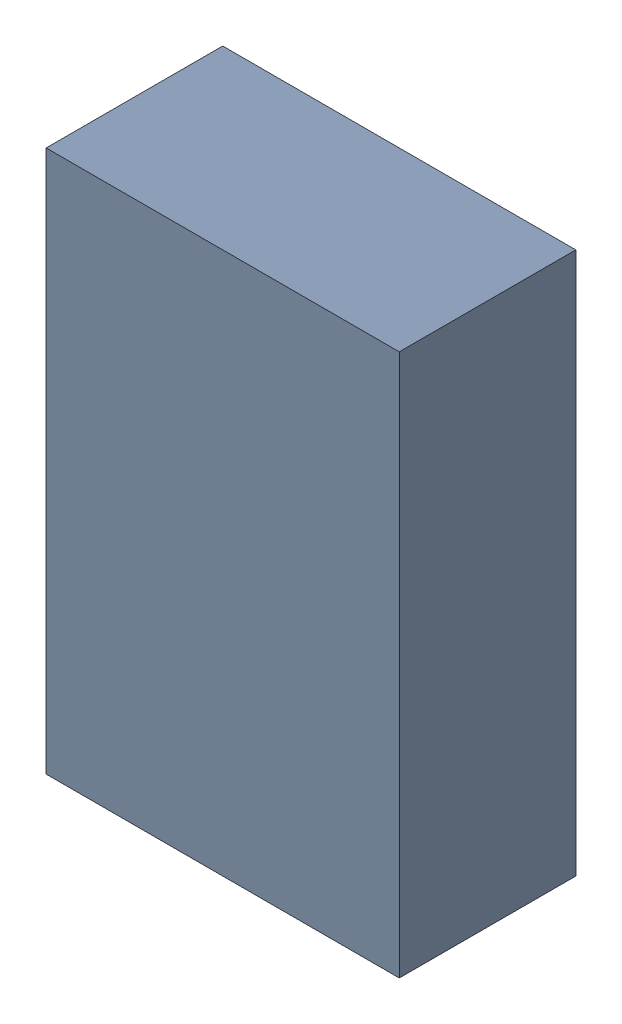
SolidWorks assembly R6-2, configuration Default. Lengths in mm.
Overall size (1.4 2.15 0.7).
2 component instances, 1 part files, 0 mates.
Components (placement in the parent):
- 959208120-2-1: 959208120-2 [Default] at (122.9827 82.385 0) size (1.4 2.15 0.7)
  - Extruded-82-1: Extruded-82 [Default] at origin size (1.4 2.15 0.7)
